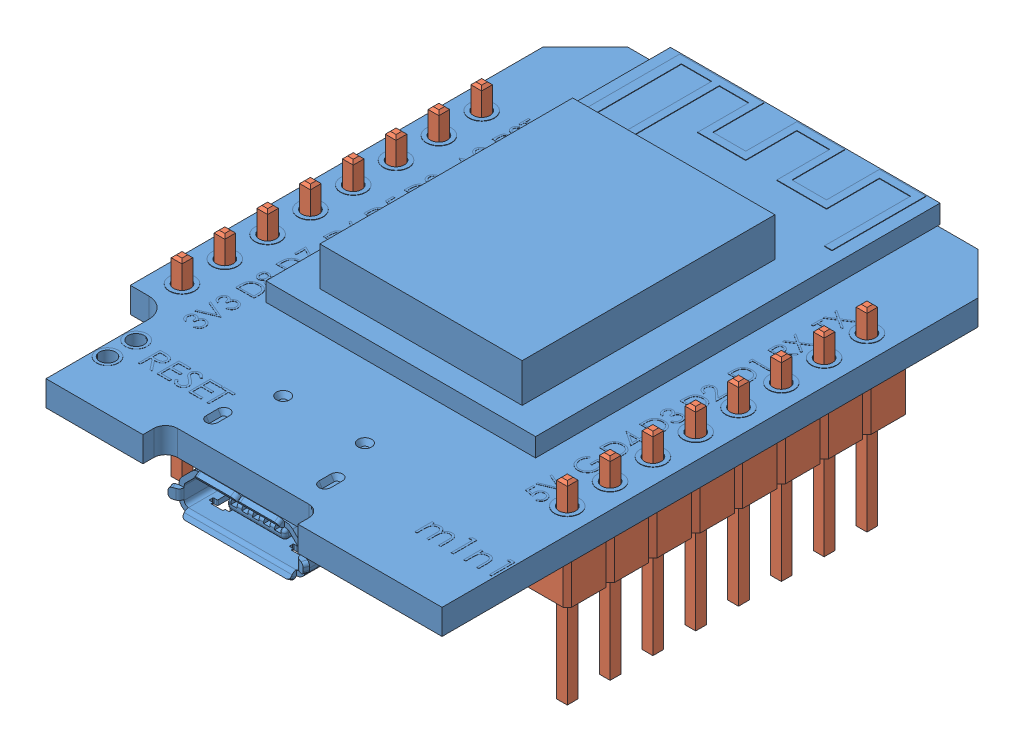
SolidWorks assembly Wemos-D1-Mini, configuration Standard. Lengths in mm.
Overall size (25.8 13.44 34.45).
3 component instances, 2 part files, 6 mates.
Components (placement in the parent):
- WEMOS-D1-mini_detailed-1: WEMOS-D1-mini_detailed [Default] at (9.8416 0.0425 51.675) size (25.8 7.6 34.45)
- Pin_header_str_1x08_p2_54mm-1: Pin_header_str_1x08_p2_54mm [Standard] at (-14.4884 0.0425 24.995) x (-1 0 0) z (0 -1 0) size (2.54 20.32 11.54)
- Pin_header_str_1x08_p2_54mm-2: Pin_header_str_1x08_p2_54mm [Standard] at (8.3716 0.0425 42.775) x (1 0 0) z (0 -1 0) size (2.54 20.32 11.54)
Mates (geometry in assembly coordinates):
- Deckungsgleich1: coincident: plane of WEMOS-D1-mini_detailed-1 through (0.5916 0.0425 51.025) normal (0 -1 0); plane of Pin_header_str_1x08_p2_54mm-1 through (-14.4884 0.0425 33.885) normal (0 1 0)
- Konzentrisch1: concentric: cylinder of WEMOS-D1-mini_detailed-1 through (-14.4884 1.5425 42.775) axis (0 -1 0) radius 0.5; point of Pin_header_str_1x08_p2_54mm-1
- Konzentrisch3: concentric: cylinder of WEMOS-D1-mini_detailed-1 through (-14.4884 1.5425 24.995) axis (0 -1 0) radius 0.5; point of Pin_header_str_1x08_p2_54mm-1
- Deckungsgleich5: coincident: plane of WEMOS-D1-mini_detailed-1 through (0.5916 0.0425 51.025) normal (0 -1 0); plane of Pin_header_str_1x08_p2_54mm-2 through (8.3716 0.0425 33.885) normal (0 1 0)
- Konzentrisch4: concentric: cylinder of WEMOS-D1-mini_detailed-1 through (8.3716 1.5425 24.995) axis (0 -1 0) radius 0.5; point of Pin_header_str_1x08_p2_54mm-2
- Konzentrisch5: concentric: cylinder of WEMOS-D1-mini_detailed-1 through (8.3716 1.5425 42.775) axis (0 -1 0) radius 0.5; point of Pin_header_str_1x08_p2_54mm-2
